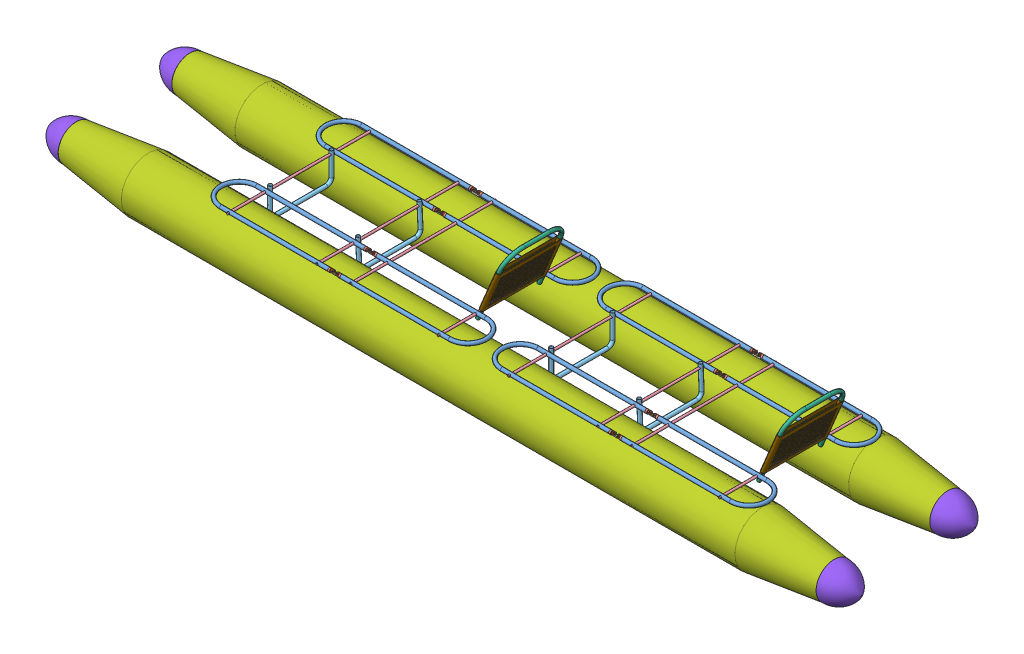
SolidWorks assembly VersionDoble, configuration Default. Lengths in mm.
Overall size (4513.76 707.27 1066.08).
62 component instances, 9 part files, 6 mates.
Components (placement in the parent):
- Frame-1: Frame [Default] at (-348.1986 -46.3779 -87.0228) size (1488 486.47 807.68)
  - FrameOneSideNoAnim-1: FrameOneSideNoAnim [Default] at (577.8554 752.7862 1416.0585) size (1488 20 220)
    - F1-1: F1 [Default<As Welded>] at (120.0879 35.9229 252.3231) size (710 20 220)
    - H1-1: H1 [Default] at (120.0879 35.9229 252.3231) x (0 1 0) z (-1 0 0) size (20 20 40)
    - H2-1: H2 [Default] at (166.0879 29.9229 252.3231) x (1 0 0) z (0 1 0) size (36 12 6)
    - H1-2: H1 [Default] at (188.0879 35.9229 252.3231) x (0 1 0) z (1 0 0) size (20 20 40)
    - H2-2: H2 [Default] at (166.0879 29.9229 52.3231) x (1 0 0) z (0 1 0) size (36 12 6)
    - H1-4: H1 [Default] at (188.0879 35.9229 52.3231) x (0 1 0) z (1 0 0) size (20 20 40)
    - H1-6: H1 [Default] at (120.0879 35.9229 52.3231) x (0 1 0) z (-1 0 0) size (20 20 40)
    - F1-2: F1 [Default<As Welded>] at (188.0879 35.9229 52.3231) x (-1 0 0) z (0 0 -1) size (710 20 220)
  - FrameOneSideNoAnim-2: FrameOneSideNoAnim [Default] at (577.8554 752.7862 834.315) size (1488 20 220)
    - F1-1: F1 [Default<As Welded>] at (120.0879 35.9229 252.3231) size (710 20 220)
    - H1-1: H1 [Default] at (120.0879 35.9229 252.3231) x (0 1 0) z (-1 0 0) size (20 20 40)
    - H2-1: H2 [Default] at (166.0879 29.9229 252.3231) x (1 0 0) z (0 1 0) size (36 12 6)
    - H1-2: H1 [Default] at (188.0879 35.9229 252.3231) x (0 1 0) z (1 0 0) size (20 20 40)
    - H2-2: H2 [Default] at (166.0879 29.9229 52.3231) x (1 0 0) z (0 1 0) size (36 12 6)
    - H1-4: H1 [Default] at (188.0879 35.9229 52.3231) x (0 1 0) z (1 0 0) size (20 20 40)
    - H1-6: H1 [Default] at (120.0879 35.9229 52.3231) x (0 1 0) z (-1 0 0) size (20 20 40)
    - F1-2: F1 [Default<As Welded>] at (188.0879 35.9229 52.3231) x (-1 0 0) z (0 0 -1) size (710 20 220)
  - F2-1: F2 [Default] at (147.9433 788.709 883.2223) x (0.974991 0.222245 0) z (0 0 1) size (12 12 800)
  - F2-2: F2 [Default] at (637.9433 788.709 877.7586) x (-0.420932 0.907092 0) z (0 0 1) size (12 12 800)
  - F2-3: F2 [Default] at (825.9433 788.709 876.0371) x (-0.580942 -0.813945 0) z (0 0 1) size (12 12 800)
  - F2-4: F2 [Default] at (1315.9433 788.709 883.7191) x (-0.357466 -0.933926 0) z (0 0 1) size (12 12 800)
  - F3-1: F3 [Default<As Welded>] at (147.9398 808.709 1446.6074) x (0 0 -1) z (1 0.000171 0) size (400 170 20)
  - F3-2: F3 [Default<As Welded>] at (636.9986 808.6867 1448.5287) x (0 0 -1) z (0.998884 0.047235 0) size (400 170 20)
  - F4-1: F4 [Default<As Welded>] at (1296.7167 742.5534 1103.7931) x (0 0 -1) z (0.923112 -0.38453 0) size (360 410 20)
- Ponton-2: Ponton [Default] at (3951.326 2252.0816 396.7892) x (0 -0.78245 -0.622713) z (-1 0 0) size (300 300 4500)
  - P1-1: P1 [Default] at (1009.5571 1409.7476 1284.8904) size (300 300 4200)
  - P2-1: P2 [Default] at (1009.5571 1409.7476 884.8904) size (200 200 150)
  - P2-2: P2 [Default] at (1009.5571 1409.7476 5084.8904) x (-0.923728 -0.383049 0) z (0 0 -1) size (200 200 150)
- Ponton-3: Ponton [Default] at (-2004.6989 -1140.8148 1327.6817) x (0 0.666514 -0.745492) z (1 0 0) size (300 300 4500)
  - P1-1: P1 [Default] at (1009.5571 1409.7476 1284.8904) size (300 300 4200)
  - P2-1: P2 [Default] at (1009.5571 1409.7476 884.8904) size (200 200 150)
  - P2-2: P2 [Default] at (1009.5571 1409.7476 5084.8904) x (-0.923728 -0.383049 0) z (0 0 -1) size (200 200 150)
- Frame-2: Frame [Default] at (1209.5074 -46.3779 -87.0228) size (1488 486.47 807.68)
  - FrameOneSideNoAnim-1: FrameOneSideNoAnim [Default] at (577.8554 752.7862 1416.0585) size (1488 20 220)
    - F1-1: F1 [Default<As Welded>] at (120.0879 35.9229 252.3231) size (710 20 220)
    - H1-1: H1 [Default] at (120.0879 35.9229 252.3231) x (0 1 0) z (-1 0 0) size (20 20 40)
    - H2-1: H2 [Default] at (166.0879 29.9229 252.3231) x (1 0 0) z (0 1 0) size (36 12 6)
    - H1-2: H1 [Default] at (188.0879 35.9229 252.3231) x (0 1 0) z (1 0 0) size (20 20 40)
    - H2-2: H2 [Default] at (166.0879 29.9229 52.3231) x (1 0 0) z (0 1 0) size (36 12 6)
    - H1-4: H1 [Default] at (188.0879 35.9229 52.3231) x (0 1 0) z (1 0 0) size (20 20 40)
    - H1-6: H1 [Default] at (120.0879 35.9229 52.3231) x (0 1 0) z (-1 0 0) size (20 20 40)
    - F1-2: F1 [Default<As Welded>] at (188.0879 35.9229 52.3231) x (-1 0 0) z (0 0 -1) size (710 20 220)
  - FrameOneSideNoAnim-2: FrameOneSideNoAnim [Default] at (577.8554 752.7862 834.315) size (1488 20 220)
    - F1-1: F1 [Default<As Welded>] at (120.0879 35.9229 252.3231) size (710 20 220)
    - H1-1: H1 [Default] at (120.0879 35.9229 252.3231) x (0 1 0) z (-1 0 0) size (20 20 40)
    - H2-1: H2 [Default] at (166.0879 29.9229 252.3231) x (1 0 0) z (0 1 0) size (36 12 6)
    - H1-2: H1 [Default] at (188.0879 35.9229 252.3231) x (0 1 0) z (1 0 0) size (20 20 40)
    - H2-2: H2 [Default] at (166.0879 29.9229 52.3231) x (1 0 0) z (0 1 0) size (36 12 6)
    - H1-4: H1 [Default] at (188.0879 35.9229 52.3231) x (0 1 0) z (1 0 0) size (20 20 40)
    - H1-6: H1 [Default] at (120.0879 35.9229 52.3231) x (0 1 0) z (-1 0 0) size (20 20 40)
    - F1-2: F1 [Default<As Welded>] at (188.0879 35.9229 52.3231) x (-1 0 0) z (0 0 -1) size (710 20 220)
  - F2-1: F2 [Default] at (147.9433 788.709 883.2223) x (0.974991 0.222245 0) z (0 0 1) size (12 12 800)
  - F2-2: F2 [Default] at (637.9433 788.709 877.7586) x (-0.420932 0.907092 0) z (0 0 1) size (12 12 800)
  - F2-3: F2 [Default] at (825.9433 788.709 876.0371) x (-0.580942 -0.813945 0) z (0 0 1) size (12 12 800)
  - F2-4: F2 [Default] at (1315.9433 788.709 883.7191) x (-0.357466 -0.933926 0) z (0 0 1) size (12 12 800)
  - F3-1: F3 [Default<As Welded>] at (147.9398 808.709 1446.6074) x (0 0 -1) z (1 0.000171 0) size (400 170 20)
  - F3-2: F3 [Default<As Welded>] at (636.9986 808.6867 1448.5287) x (0 0 -1) z (0.998884 0.047235 0) size (400 170 20)
  - F4-1: F4 [Default<As Welded>] at (1296.7167 742.5534 1103.7931) x (0 0 -1) z (0.923112 -0.38453 0) size (360 410 20)
- T1-1: T1 [Default] at (2529.2893 751.5463 1016.7703) x (0 0 1) z (-0.923112 0.38453 0) size (363 240 23)
- T1-2: T1 [Default] at (971.25 750.7462 1016.7703) x (0 0 1) z (-0.923112 0.38453 0) size (363 240 23)
Mates (geometry in assembly coordinates):
- Coincident3: coincident anti-aligned: line of Frame-1/FrameOneSideNoAnim-1/F1-2 through (417.7446 742.3312 1381.3588) axis (1 0 0); line of Frame-2/FrameOneSideNoAnim-1/F1-1 through (1907.4507 742.3312 1381.3588) axis (-1 0 0)
- Coincident4: coincident anti-aligned: line of Frame-1/FrameOneSideNoAnim-2/F1-2 through (417.7446 742.3312 799.6153) axis (1 0 0); line of Frame-2/FrameOneSideNoAnim-2/F1-1 through (1907.4507 742.3312 799.6153) axis (-1 0 0)
- Coincident5: coincident anti-aligned: line of Frame-2/F4-1 through (2506.2241 696.1756 1016.7703) axis (0.38453 0.923112 0); line of T1-1 through (2621.5766 973.0933 1016.7703) axis (-0.38453 -0.923112 0)
- Coincident6: coincident anti-aligned: line of Frame-2/F4-1 through (2506.2241 696.1756 1356.7703) axis (0.38453 0.923112 0); line of T1-1 through (2621.5766 973.0933 1356.7703) axis (-0.38453 -0.923112 0)
- Coincident9: coincident anti-aligned: line of Frame-1/F4-1 through (948.5181 696.1756 1016.7703) axis (0.38453 0.923112 0); line of T1-2 through (1063.5372 972.2932 1016.7703) axis (-0.38453 -0.923112 0)
- Coincident10: coincident anti-aligned: line of Frame-1/F4-1 through (948.5181 696.1756 1356.7703) axis (0.38453 0.923112 0); line of T1-2 through (1063.5372 972.2932 1356.7703) axis (-0.38453 -0.923112 0)
